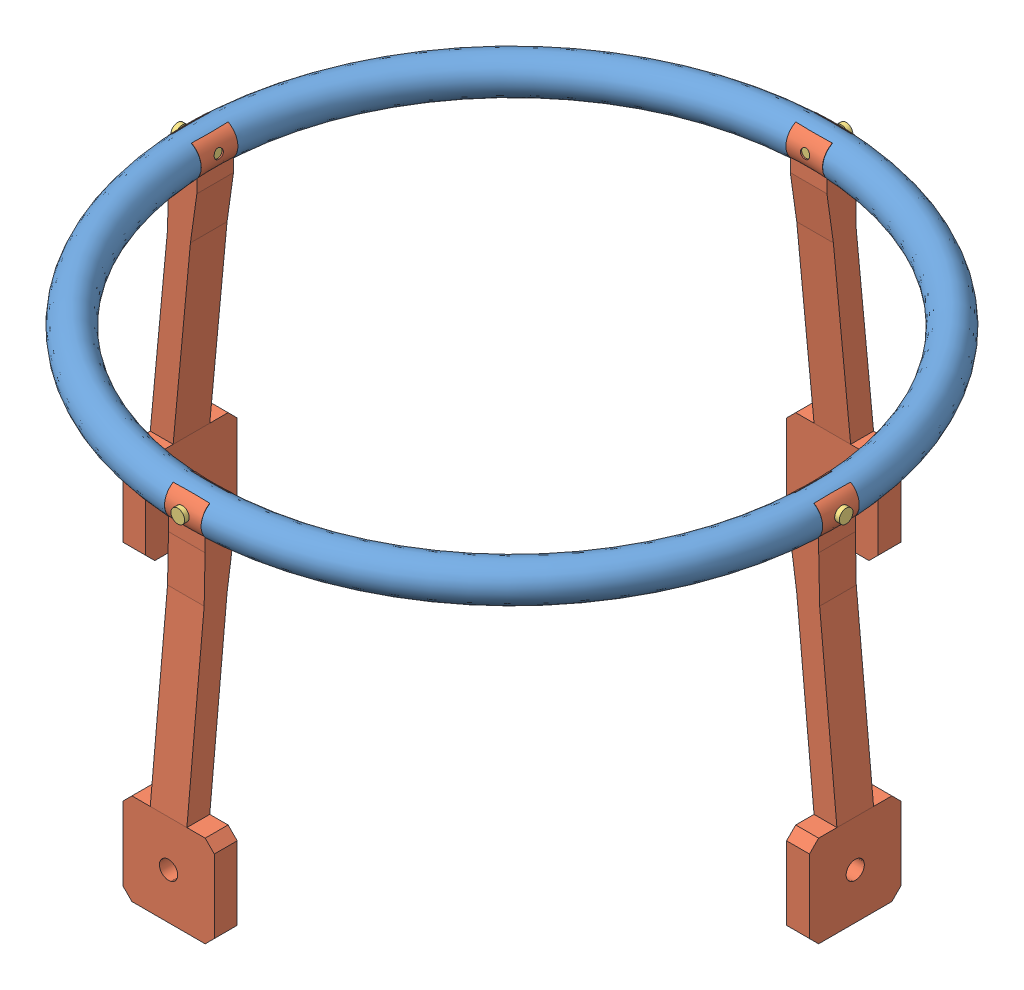
SolidWorks assembly Assem5, configuration Default. Lengths in mm.
Overall size (150 79.4 150).
9 component instances, 3 part files, 20 mates.
Components (placement in the parent):
- SE_01_2_4001-1: SE_01_2_4001 [Default] at origin size (144.19 8.22 144.19)
- SE_01_2_4002-1: SE_01_2_4002 [Default] at (-4 -5.3956 72.7809) x (0 -1 0) z (1 0 0) size (79.08 11.37 20)
- SE_01_2_4002-2: SE_01_2_4002 [Default] at (-72.7809 -5.3956 -4) x (0 -1 0) z (0 0 1) size (79.08 11.37 20)
- SE_01_2_4002-3: SE_01_2_4002 [Default] at (4 -5.3956 -72.7809) x (0 -1 0) z (-1 0 0) size (79.08 11.37 20)
- SE_01_2_4002-4: SE_01_2_4002 [Default] at (72.7809 -5.3956 4) x (0 -1 0) z (0 0 -1) size (79.08 11.37 20)
- SE_01_2_4003-1: SE_01_2_4003 [Default] at (-64.3 0.5296 0.0079) x (0 0 1) z (-1 0 0) size (3 3 8.7)
- SE_01_2_4003-2: SE_01_2_4003 [Default] at (-0.0079 0.5296 -64.3) x (-0.923728 -0.383049 0) z (0 0 -1) size (3 3 8.7)
- SE_01_2_4003-3: SE_01_2_4003 [Default] at (0.0079 0.5296 64.3) size (3 3 8.7)
- SE_01_2_4003-4: SE_01_2_4003 [Default] at (64.3 0.5296 -0.0079) x (0 0 -1) z (1 0 0) size (3 3 8.7)
Mates (geometry in assembly coordinates):
- Coincident1: coincident: plane of SE_01_2_4001-1 through (-4 -4 70) normal (0 0 1); plane of SE_01_2_4002-1 through (4 -5.3956 70) normal (0 0 -1)
- Coincident2: coincident: plane of SE_01_2_4001-1 through (4 -4 70) normal (-1 0 0); plane of SE_01_2_4002-1 through (4 -5.3956 72.7809) normal (1 0 0)
- Coincident3: coincident anti-aligned: plane of SE_01_2_4001-1 through (4 -3.3956 -72.0972) normal (0 -1 0); plane of SE_01_2_4002-1 through (4 -3.3956 72.7809) normal (0 1 0)
- Coincident4: coincident: plane of SE_01_2_4001-1 through (-70 -4 -4) normal (-1 0 0); plane of SE_01_2_4002-2 through (-70 -5.3956 4) normal (1 0 0)
- Coincident5: coincident: plane of SE_01_2_4001-1 through (-70 -4 4) normal (0 0 -1); plane of SE_01_2_4002-2 through (-72.7809 -5.3956 4) normal (0 0 1)
- Coincident6: coincident anti-aligned: plane of SE_01_2_4001-1 through (72.0972 -3.3956 4) normal (0 -1 0); plane of SE_01_2_4002-2 through (-72.7809 -3.3956 4) normal (0 1 0)
- Coincident7: coincident: plane of SE_01_2_4001-1 through (4 -4 -70) normal (0 0 -1); plane of SE_01_2_4002-3 through (-4 -5.3956 -70) normal (0 0 1)
- Coincident8: coincident: plane of SE_01_2_4001-1 through (4 -4 -70) normal (-1 0 0); plane of SE_01_2_4002-3 through (4 -5.3956 -72.7809) normal (1 0 0)
- Coincident9: coincident anti-aligned: plane of SE_01_2_4001-1 through (4 -3.3956 -72.0972) normal (0 -1 0); plane of SE_01_2_4002-3 through (-4 -3.3956 -72.7809) normal (0 1 0)
- Coincident10: coincident: plane of SE_01_2_4001-1 through (70 -4 4) normal (1 0 0); plane of SE_01_2_4002-4 through (70 -5.3956 -4) normal (-1 0 0)
- Coincident11: coincident: plane of SE_01_2_4001-1 through (70 -4 4) normal (0 0 -1); plane of SE_01_2_4002-4 through (72.7809 -5.3956 4) normal (0 0 1)
- Coincident12: coincident anti-aligned: plane of SE_01_2_4001-1 through (72.0972 -3.3956 4) normal (0 -1 0); plane of SE_01_2_4002-4 through (72.7809 -3.3956 -4) normal (0 1 0)
- Concentric3: concentric: cylinder of SE_01_2_4002-2 through (-63.6312 0.5296 0.0079) axis (-1 0 0) radius 1; cylinder of SE_01_2_4003-1 through (-72 0.5296 0.0079) axis (1 0 0) radius 1
- Tangent1: tangent: torus of SE_01_2_4002-2; plane of SE_01_2_4003-1 through (-72 0.5296 0.0079) normal (1 0 0)
- Concentric4: concentric: cylinder of SE_01_2_4002-3 through (-0.0079 0.5296 -63.6312) axis (0 0 -1) radius 1; cylinder of SE_01_2_4003-2 through (-0.0079 0.5296 -72) axis (0 0 1) radius 1
- Tangent2: tangent: torus of SE_01_2_4002-3; plane of SE_01_2_4003-2 through (-0.0079 0.5296 -72) normal (0 0 1)
- Concentric5: concentric: cylinder of SE_01_2_4002-1 through (0.0079 0.5296 63.6312) axis (0 0 1) radius 1; cylinder of SE_01_2_4003-3 through (0.0079 0.5296 72) axis (0 0 -1) radius 1
- Tangent3: tangent: torus of SE_01_2_4002-1; plane of SE_01_2_4003-3 through (0.0079 0.5296 72) normal (0 0 -1)
- Concentric6: concentric: cylinder of SE_01_2_4002-4 through (63.6312 0.5296 -0.0079) axis (1 0 0) radius 1; cylinder of SE_01_2_4003-4 through (72 0.5296 -0.0079) axis (-1 0 0) radius 1
- Tangent4: tangent: torus of SE_01_2_4002-4; plane of SE_01_2_4003-4 through (72 0.5296 -0.0079) normal (-1 0 0)
